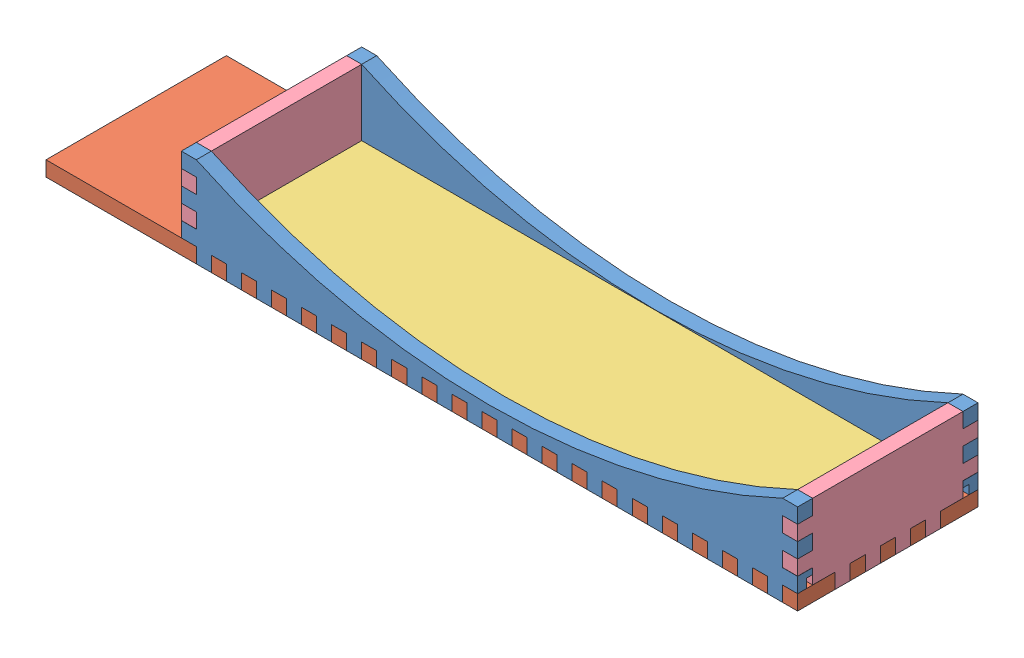
SolidWorks assembly Assemblage1, configuration Défaut. Lengths in mm.
Overall size (250 30 60).
6 component instances, 4 part files, 15 mates.
Components (placement in the parent):
- Coté bras-1: Coté bras [Défaut] at (-58.2884 73.1748 202.5) size (205 30 5)
- Fond bras-1: Fond bras [Défaut] at (-84.4308 23.7217 210.7561) x (1 0 0) z (0 1 0) size (250 60 5)
- Métal-1: Métal [Défaut] at (34.8419 31.7217 213.3894) x (1 0 0) z (0 -1 0) size (195 54 3)
- Coté bras-2: Coté bras [Défaut] at (54.6927 73.1748 262.5) x (-1 0 0) z (0 0 -1) size (205 30 5)
- Début, fin bras-1: Début, fin bras [Défaut] at (100.7022 15.8142 166.4784) x (0 0 -1) z (-1 0 0) size (60 30 5)
- Début, fin bras-2: Début, fin bras [Défaut] at (-99.2978 15.8142 166.4784) x (0 0 -1) z (-1 0 0) size (60 30 5)
Mates (geometry in assembly coordinates):
- Coïncidente3: coincident anti-aligned: plane of Fond bras-1 through (-84.4308 28.7217 210.7561) normal (0 1 0); plane of Coté bras-2 through (75.7022 28.7217 458.73) normal (0 -1 0)
- Coïncidente4: coincident aligned: plane of Fond bras-1 through (100.7022 28.7217 202.5) normal (1 0 0); plane of Coté bras-2 through (100.7022 53.7217 257.5) normal (1 0 0)
- Coïncidente7: coincident aligned: plane of Coté bras-1 through (100.7022 53.7217 207.5) normal (1 0 0); plane of Fond bras-1 through (100.7022 28.7217 202.5) normal (1 0 0)
- Coïncidente8: coincident anti-aligned: plane of Coté bras-1 through (100.7022 28.7217 6.27) normal (0 -1 0); plane of Fond bras-1 through (-84.4308 28.7217 210.7561) normal (0 1 0)
- Coïncidente9: coincident anti-aligned: plane of Fond bras-1 through (-84.4308 28.7217 210.7561) normal (0 1 0); plane of Métal-1 through (34.8419 28.7217 213.3894) normal (0 -1 0)
- Coïncidente11: coincident anti-aligned: plane of Métal-1 through (-99.2978 28.7217 259.5) normal (0 0 1); plane of Coté bras-2 through (54.6927 73.1748 259.5) normal (0 0 -1)
- Coïncidente12: coincident aligned: plane of Fond bras-1 through (-149.2978 28.7217 262.5) normal (0 0 1); plane of Coté bras-2 through (54.6927 73.1748 262.5) normal (0 0 1)
- Coïncidente13: coincident aligned: plane of Coté bras-1 through (-58.2884 73.1748 202.5) normal (0 0 -1); plane of Fond bras-1 through (-149.2978 28.7217 202.5) normal (0 0 -1)
- Coïncidente15: coincident aligned: plane of Métal-1 through (95.7022 28.7217 259.5) normal (1 0 0); plane of Coté bras-2 through (95.7022 33.7217 458.73) normal (1 0 0)
- Coïncidente18: coincident aligned: plane of Coté bras-2 through (100.7022 53.7217 257.5) normal (0 1 0); plane of Début, fin bras-1 through (95.7022 53.7217 232.5) normal (0 1 0)
- Coïncidente19: coincident aligned: plane of Coté bras-2 through (54.6927 73.1748 262.5) normal (0 0 1); plane of Début, fin bras-1 through (95.7022 23.7217 262.5) normal (0 0 1)
- Coïncidente20: coincident aligned: plane of Fond bras-1 through (100.7022 28.7217 202.5) normal (1 0 0); plane of Début, fin bras-1 through (100.7022 15.8142 166.4784) normal (1 0 0)
- Coïncidente22: coincident aligned: plane of Coté bras-1 through (-104.2978 53.7217 207.5) normal (0 1 0); plane of Début, fin bras-2 through (-104.2978 53.7217 232.5) normal (0 1 0)
- Coïncidente23: coincident aligned: plane of Coté bras-1 through (-58.2884 73.1748 202.5) normal (0 0 -1); plane of Début, fin bras-2 through (-104.2978 23.7217 202.5) normal (0 0 -1)
- Coïncidente24: coincident aligned: plane of Coté bras-1 through (-104.2978 53.7217 207.5) normal (-1 0 0); plane of Début, fin bras-2 through (-104.2978 15.8142 166.4784) normal (-1 0 0)
